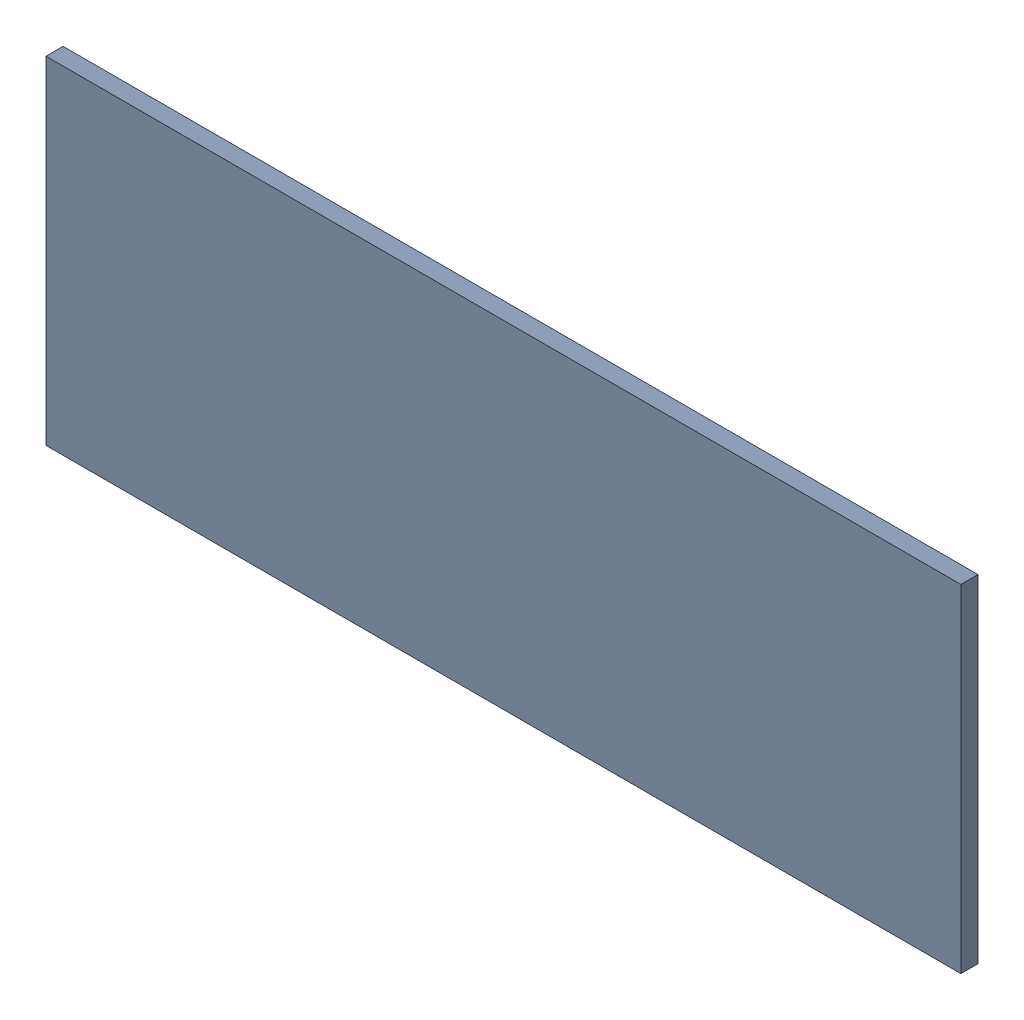
SolidWorks assembly Pad RAK4600-5(14.5mm,22.5mm) on Top Layer, configuration Predeterminado. Lengths in mm.
Overall size (1.9 0.7 0.04).
2 component instances, 1 part files, 0 mates.
Components (placement in the parent):
- Pad RAK4600-5(14.5mm,22.5mm) on Top Layer-1-1: Pad RAK4600-5(14.5mm,22.5mm) on Top Layer-1 [Predeterminado] at (-68.317 -44.187 -0.0457) size (1.9 0.7 0.04)
  - Pad RAK4600-5(14.5mm,22.5mm) on Top Layer-Part-1-1: Pad RAK4600-5(14.5mm,22.5mm) on Top Layer-Part-1 [Predeterminado] at origin size (1.9 0.7 0.04)
